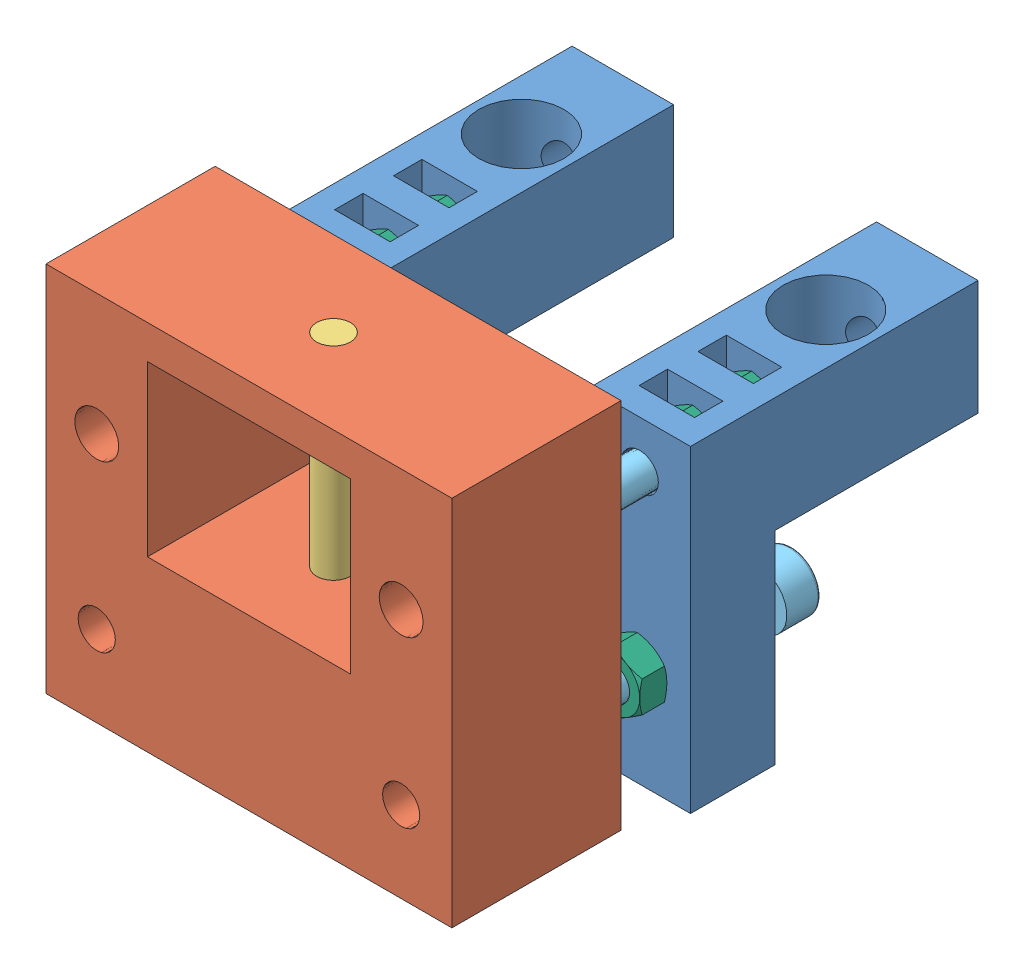
SolidWorks assembly Y tensioner, configuration Default. Lengths in mm.
Overall size (60 58 77.77).
15 component instances, 6 part files, 30 mates.
Components (placement in the parent):
- Y tensioner part 1-1: Y tensioner part 1 [Default] at (-20.8115 -2.7831 12.8728) size (15 47 42.5)
- Y tensioner part 1-2: Y tensioner part 1 [Default] at (24.1885 -2.7831 12.8728) size (15 47 42.5)
- Y tensioner part 2-1: Y tensioner part 2 [Default] at (-20.8115 0.2169 90.6395) size (60 55 25)
- pulley shaft-1: pulley shaft [Default] at (9.1885 6.9669 78.1395) x (1 0 0) z (0 1 0) size (5 5 48.25)
- m6 10 mm countersunk head screw-1: m6 10 mm countersunk head screw [Default] at (31.6885 34.4169 27.8728) x (0 -1 0) z (-0.024452 0 0.999701) size (10 12 12)
- m5 40 mm socket heade screw-6: m5 40 mm socket heade screw [Default] at (31.6885 12.2169 37.8728) x (0 0 1) z (-1 0 0) size (45 8.5 8.5)
- m5 40 mm socket heade screw-7: m5 40 mm socket heade screw [Default] at (-13.3115 12.2169 37.8728) x (0 0 1) z (-1 0 0) size (45 8.5 8.5)
- m5 40 mm socket heade screw-8: m5 40 mm socket heade screw [Default] at (-13.3115 37.2169 72.1395) x (0 0 -1) z (0.883668 0.468115 0) size (45 8.5 8.5)
- m5 40 mm socket heade screw-9: m5 40 mm socket heade screw [Default] at (31.6885 37.2169 72.1395) x (0 0 -1) z (1 0 0) size (45 8.5 8.5)
- M5 nut-7: M5 nut [Default] at (-13.3115 37.2169 47.1728) x (0 0 1) z (-1 0 0) size (4 9.24 8)
- M5 nut-8: M5 nut [Default] at (-13.3115 37.2169 38.4728) x (0 0 1) z (-1 0 0) size (4 9.24 8)
- M5 nut-9: M5 nut [Default] at (31.6885 37.2169 38.4728) x (0 0 1) z (-1 0 0) size (4 9.24 8)
- M5 nut-10: M5 nut [Default] at (31.6885 37.2169 47.1728) x (0 0 1) z (-1 0 0) size (4 9.24 8)
- M5 nut-11: M5 nut [Default] at (31.6885 12.2169 59.3728) x (0 0 -1) z (1 0 0) size (4 9.24 8)
- M5 nut-12: M5 nut [Default] at (-13.3115 12.2169 59.3728) x (0 0 -1) z (1 0 0) size (4 9.24 8)
Mates (geometry in assembly coordinates):
- Coincident1: coincident aligned: plane of Y tensioner part 1-1 through (-5.8115 27.2169 12.8728) normal (0 -1 0); plane of Y tensioner part 1-2 through (39.1885 27.2169 12.8728) normal (0 -1 0)
- Coincident2: coincident aligned: plane of Y tensioner part 1-1 through (-5.8115 -2.7831 42.8728) normal (0 0 -1); plane of Y tensioner part 1-2 through (39.1885 -2.7831 42.8728) normal (0 0 -1)
- Distance1: distance = 30 mm anti-aligned: plane of Y tensioner part 1-1 through (-5.8115 -2.7831 55.3728) normal (1 0 0); plane of Y tensioner part 1-2 through (24.1885 -2.7831 55.3728) normal (-1 0 0)
- Parallel1: parallel aligned: plane of Y tensioner part 1-2 through (24.1885 44.2169 55.3728) normal (0 1 0); plane of Y tensioner part 2-1 through (-20.8115 55.2169 90.6395) normal (0 1 0)
- Concentric24: concentric anti-aligned: cylinder of Y tensioner part 2-1 through (9.1885 0.2169 78.1395) axis (0 1 0) radius 2.5; cylinder of pulley shaft-1 through (9.1885 55.2169 78.1395) axis (0 -1 0) radius 2.5
- Coincident29: coincident aligned: plane of Y tensioner part 2-1 through (-20.8115 55.2169 90.6395) normal (0 1 0); plane of pulley shaft-1 through (9.1885 55.2169 78.1395) normal (0 1 0)
- Concentric25: concentric aligned: cylinder of Y tensioner part 1-2 through (31.6885 34.4169 27.8728) axis (0 1 0) radius 3.3; cylinder of m6 10 mm countersunk head screw-1 through (31.6885 34.4169 27.8728) axis (0 1 0) radius 3
- Coincident30: coincident anti-aligned: circle of Y tensioner part 1-2; plane of m6 10 mm countersunk head screw-1 through (37.6867 34.4169 28.0195) normal (0 1 0)
- Concentric28: concentric aligned: cylinder of Y tensioner part 1-1 through (-13.3115 12.2169 40.3728) axis (0 0 1) radius 2.75; cylinder of Y tensioner part 2-1 through (-13.3115 12.2169 65.6395) axis (0 0 1) radius 2.75
- Concentric29: concentric anti-aligned: cylinder of Y tensioner part 1-1 through (-13.3115 12.2169 40.3728) axis (0 0 1) radius 2.75; cylinder of m5 40 mm socket heade screw-7 through (-13.3115 12.2169 37.8728) axis (0 0 -1) radius 2.5
- Distance2: distance = 5 mm anti-aligned: plane of Y tensioner part 1-1 through (-5.8115 -2.7831 42.8728) normal (0 0 -1); plane of m5 40 mm socket heade screw-7 through (-13.3115 12.2169 37.8728) normal (0 0 1)
- Concentric30: concentric anti-aligned: cylinder of Y tensioner part 1-2 through (31.6885 12.2169 40.3728) axis (0 0 1) radius 2.75; cylinder of m5 40 mm socket heade screw-6 through (31.6885 12.2169 37.8728) axis (0 0 -1) radius 2.5
- Coincident32: coincident aligned: plane of m5 40 mm socket heade screw-6 through (31.6885 16.0419 32.8728) normal (0 0 -1); plane of m5 40 mm socket heade screw-7 through (-13.3115 16.0419 32.8728) normal (0 0 -1)
- Concentric31: concentric anti-aligned: cylinder of Y tensioner part 2-1 through (-13.3115 37.2169 77.1395) axis (0 0 -1) radius 4.45; cylinder of m5 40 mm socket heade screw-8 through (-13.3115 37.2169 72.1395) axis (0 0 1) radius 2.5
- Coincident33: coincident anti-aligned: plane of Y tensioner part 2-1 through (-13.3115 37.2169 77.1395) normal (0 0 -1); plane of m5 40 mm socket heade screw-8 through (-15.102 40.5969 77.1395) normal (0 0 1)
- Concentric32: concentric anti-aligned: cylinder of Y tensioner part 2-1 through (31.6885 37.2169 77.1395) axis (0 0 -1) radius 4.45; cylinder of m5 40 mm socket heade screw-9 through (31.6885 37.2169 72.1395) axis (0 0 1) radius 2.5
- Coincident34: coincident anti-aligned: plane of Y tensioner part 2-1 through (31.6885 37.2169 77.1395) normal (0 0 -1); plane of m5 40 mm socket heade screw-9 through (31.6885 41.0419 77.1395) normal (0 0 1)
- Concentric33: concentric anti-aligned: cylinder of Y tensioner part 1-2 through (31.6885 37.2169 40.3728) axis (0 0 1) radius 2.75; cylinder of M5 nut-10 through (31.6885 37.2169 47.1728) axis (0 0 -1) radius 2.067
- Coincident35: coincident anti-aligned: plane of Y tensioner part 1-2 through (27.5885 32.2169 47.1728) normal (0 0 1); plane of M5 nut-10 through (31.6885 34.7169 47.1728) normal (0 0 -1)
- Concentric34: concentric anti-aligned: cylinder of Y tensioner part 1-2 through (31.6885 37.2169 40.3728) axis (0 0 1) radius 2.75; cylinder of M5 nut-9 through (31.6885 37.2169 38.4728) axis (0 0 -1) radius 2.067
- Coincident36: coincident anti-aligned: plane of Y tensioner part 1-2 through (27.5885 32.2169 38.4728) normal (0 0 1); plane of M5 nut-9 through (31.6885 34.7169 38.4728) normal (0 0 -1)
- Concentric35: concentric anti-aligned: cylinder of Y tensioner part 1-1 through (-13.3115 37.2169 40.3728) axis (0 0 1) radius 2.75; cylinder of M5 nut-7 through (-13.3115 37.2169 47.1728) axis (0 0 -1) radius 2.067
- Coincident37: coincident anti-aligned: plane of Y tensioner part 1-1 through (-17.4115 32.2169 47.1728) normal (0 0 1); plane of M5 nut-7 through (-13.3115 34.7169 47.1728) normal (0 0 -1)
- Concentric36: concentric anti-aligned: cylinder of Y tensioner part 1-1 through (-13.3115 37.2169 40.3728) axis (0 0 1) radius 2.75; cylinder of M5 nut-8 through (-13.3115 37.2169 38.4728) axis (0 0 -1) radius 2.067
- Coincident38: coincident anti-aligned: plane of Y tensioner part 1-1 through (-17.4115 32.2169 38.4728) normal (0 0 1); plane of M5 nut-8 through (-13.3115 34.7169 38.4728) normal (0 0 -1)
- LimitDistance1: limit distance = 6.3333 mm aligned: plane of m5 40 mm socket heade screw-8 through (-13.3115 37.2169 32.1395) normal (0 0 -1); plane of M5 nut-8 through (-13.3115 34.7169 38.4728) normal (0 0 -1)
- Concentric37: concentric anti-aligned: cylinder of m5 40 mm socket heade screw-7 through (-13.3115 12.2169 37.8728) axis (0 0 -1) radius 2.5; cylinder of M5 nut-12 through (-13.3115 12.2169 59.3728) axis (0 0 1) radius 2.067
- Coincident41: coincident anti-aligned: plane of Y tensioner part 1-1 through (-20.8115 -2.7831 55.3728) normal (0 0 1); plane of M5 nut-12 through (-13.3115 8.2169 55.3728) normal (0 0 -1)
- Concentric38: concentric anti-aligned: cylinder of m5 40 mm socket heade screw-6 through (31.6885 12.2169 37.8728) axis (0 0 -1) radius 2.5; cylinder of M5 nut-11 through (31.6885 12.2169 59.3728) axis (0 0 1) radius 2.067
- Coincident42: coincident anti-aligned: plane of Y tensioner part 1-2 through (24.1885 -2.7831 55.3728) normal (0 0 1); plane of M5 nut-11 through (31.6885 8.2169 55.3728) normal (0 0 -1)
